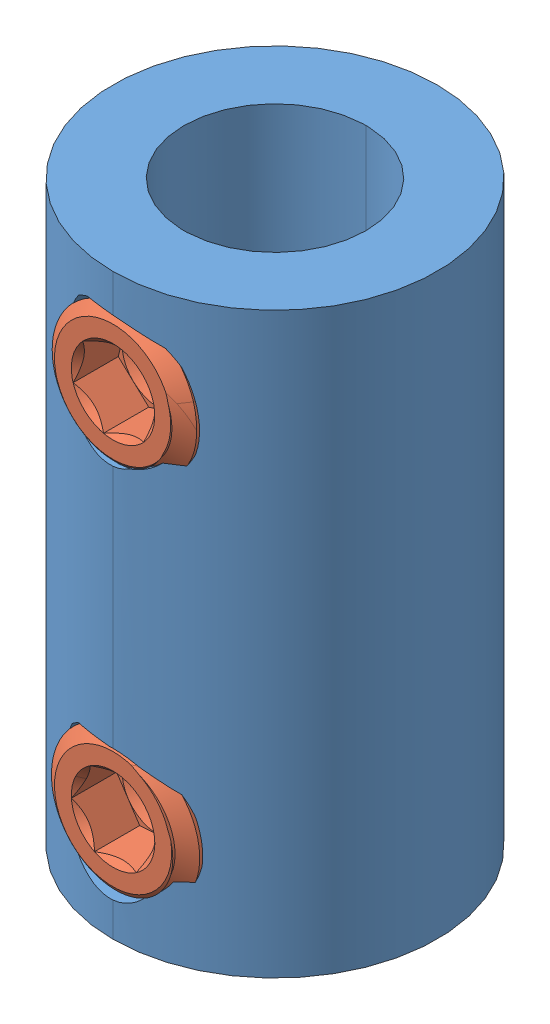
SolidWorks assembly 625106 assembly.STEP, configuration Default. Lengths in mm.
Overall size (10.67 19.05 10.67).
3 component instances, 2 part files, 0 mates.
Components (placement in the parent):
- 625106.STEP-1: 625106.STEP [Default] at (-68.9644 10.3754 22.8311) size (10.67 19.05 10.67)
- 632134_91375A436.STEP-1: 632134_91375A436.STEP [Default] at (-68.9644 13.8044 26.9749) x (-0.895963 0.444129 0) z (0 0 1) size (4.83 4.83 3.18)
- 632134_91375A436.STEP-2: 632134_91375A436.STEP [Default] at (-68.9644 25.9964 26.9749) x (-0.28947 0.957187 0) z (0 0 1) size (4.83 4.83 3.18)
